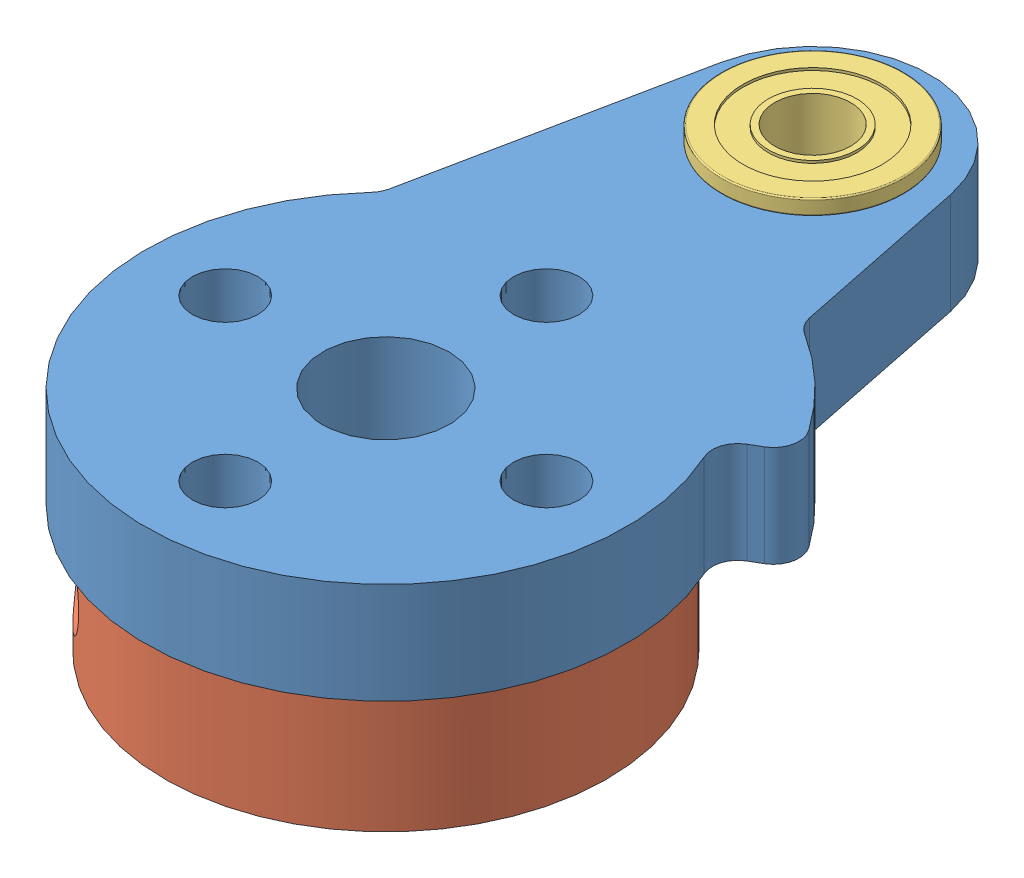
SolidWorks assembly Spider_lever_2, configuration Default. Lengths in mm.
Overall size (24.75 9.6 33.88).
4 component instances, 3 part files, 7 mates.
Components (placement in the parent):
- SLS_Lever_upper-1: SLS_Lever_upper [Default] at origin size (20.83 4 31)
- shaft_mount-1: shaft_mount [Default] at (-0.0001 -2.5001 0.0001) x (-0.707107 0 -0.707107) z (0 1 0) size (17.5 17.5 5)
- MF63zz 3x6x2.5mm Flanged Bearing.step-1: MF63zz 3x6x2.5mm Flanged Bearing.step [Default] at (0 4.6 -16.8746) x (1 0 0) z (0 -1 0) size (7.2 7.2 2.5)
- MF63zz 3x6x2.5mm Flanged Bearing.step-2: MF63zz 3x6x2.5mm Flanged Bearing.step [Default] at (0 -0.6 -16.8746) x (-1 0 0) z (0 1 0) size (7.2 7.2 2.5)
Mates (geometry in assembly coordinates):
- Concentric1: concentric anti-aligned: cylinder of SLS_Lever_upper-1 through (0 0 -6.35) axis (0 1 0) radius 1.3; cylinder of shaft_mount-1 through (0 -5 -6.35) axis (0 -1 0) radius 0.889
- Concentric2: concentric anti-aligned: cylinder of SLS_Lever_upper-1 through (0 0 6.35) axis (0 1 0) radius 1.3; cylinder of shaft_mount-1 through (0 -5 6.35) axis (0 -1 0) radius 0.889
- Concentric3: concentric aligned: circle of SLS_Lever_upper-1; cylinder of MF63zz 3x6x2.5mm Flanged Bearing.step-1 through (0 3.05 -16.8746) axis (0 1 0) radius 3
- Coincident2: coincident anti-aligned: plane of SLS_Lever_upper-1 through (0 4 -16.8746) normal (0 1 0); plane of MF63zz 3x6x2.5mm Flanged Bearing.step-1 through (-3.6 4 -16.8746) normal (0 -1 0)
- Concentric4: concentric aligned: cylinder of SLS_Lever_upper-1 through (0 4 -16.8746) axis (0 -1 0) radius 3.05; cylinder of MF63zz 3x6x2.5mm Flanged Bearing.step-2 through (0 0.95 -16.8746) axis (0 -1 0) radius 3
- Coincident3: coincident anti-aligned: plane of SLS_Lever_upper-1 through (0 0 -16.8746) normal (0 -1 0); plane of MF63zz 3x6x2.5mm Flanged Bearing.step-2 through (3.6 0 -16.8746) normal (0 1 0)
- Coincident4: coincident anti-aligned: plane of SLS_Lever_upper-1 through (0 0 -16.8746) normal (0 -1 0); plane of shaft_mount-1 through (0 0 0) normal (0 1 0)
